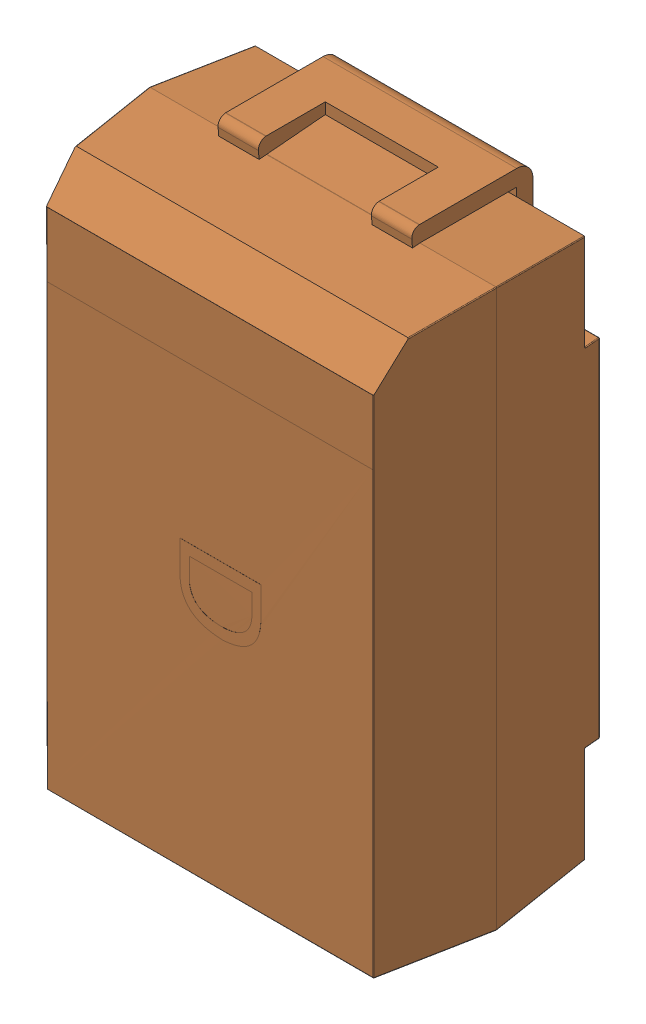
SolidWorks assembly E1, configuration 默认. Lengths in mm.
Overall size (4.3 7.3 2.85).
3 component instances, 2 part files, 0 mates.
Components (placement in the parent):
- CD_D(7343H)-1: CD_D(7343H) [默认] at (87.376 53.848 0) x (0 -1 0) z (0 0 1) size (7.3 4.3 2.85)
  - LOGO__2-1: LOGO__2 [默认] at (0 0.0355 -0.005) x (-1 0 0) z (0 0 -1) size (1.5 1.73 0.01)
  - CD_D(7343)-1: CD_D(7343) [默认] at (0 0 1.4) size (7.3 4.3 2.84)
